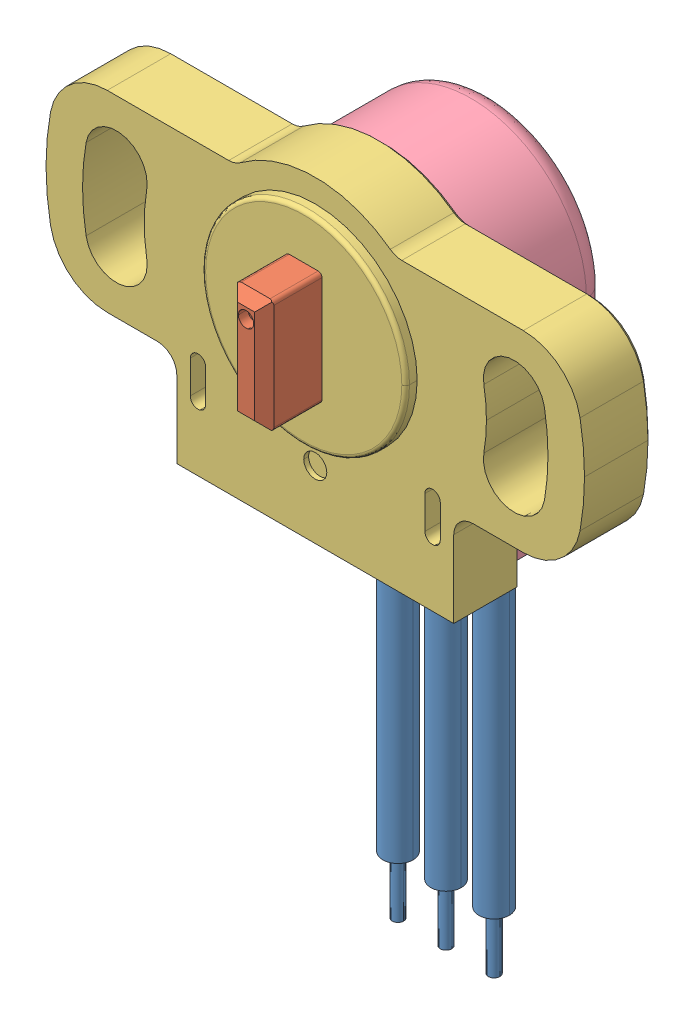
SolidWorks assembly BR-00009-DA-BPPS (MSC360-1A-C0004-ERA360-05K), configuration Default. Lengths in mm.
Overall size (28 38 12.8).
9 component instances, 4 part files, 0 mates.
Components (placement in the parent):
- MSC-360^BR-00009-DA-BPPS (MSC360-1A-C0004-ERA360-05K)-1: MSC-360^BR-00009-DA-BPPS (MSC360-1A-C0004-ERA360-05K) [Default] at origin size (28 38 12.8) (virtual)
  - 3981_subjto PCB^MSC-360_BR-00009-DA-BPPS (MSC360-1A-C0004-ERA360-05K)-1: 3981_subjto PCB^MSC-360_BR-00009-DA-BPPS (MSC360-1A-C0004-ERA360-05K) [Default] at (0 0 7.7) x (-1 0 0) z (0 0 -1) size (6.58 26 1.58) (virtual)
    - 3980_cable^3981_subjto PCB_MSC-360_BR-00009-DA-BPPS (MSC360-1A-C0004-ERA360-05K)-1: 3980_cable^3981_subjto PCB_MSC-360_BR-00009-DA-BPPS (MSC360-1A-C0004-ERA360-05K) [Default] at (0 -8.5 5.3) x (-1 0 0) z (0 -1 0) size (1.58 1.58 26) (virtual)
    - 3980_cable^3981_subjto PCB_MSC-360_BR-00009-DA-BPPS (MSC360-1A-C0004-ERA360-05K)-2: 3980_cable^3981_subjto PCB_MSC-360_BR-00009-DA-BPPS (MSC360-1A-C0004-ERA360-05K) [Default] at (2.5 -8.5 5.3) x (-1 0 0) z (0 -1 0) size (1.58 1.58 26) (virtual)
    - 3980_cable^3981_subjto PCB_MSC-360_BR-00009-DA-BPPS (MSC360-1A-C0004-ERA360-05K)-3: 3980_cable^3981_subjto PCB_MSC-360_BR-00009-DA-BPPS (MSC360-1A-C0004-ERA360-05K) [Default] at (-2.5 -8.5 5.3) x (-1 0 0) z (0 -1 0) size (1.58 1.58 26) (virtual)
  - 3987 rotor sobremoldeo^MSC-360_BR-00009-DA-BPPS (MSC360-1A-C0004-ERA360-05K)-1: 3987 rotor sobremoldeo^MSC-360_BR-00009-DA-BPPS (MSC360-1A-C0004-ERA360-05K) [Default] at (0 0 7.7) x (-1 0 0) z (0 0 1) size (1.9 5.9 3) (virtual)
    - 3987_rotor sobremoldeado^3987 rotor sobremoldeo_MSC-360_BR-00009-DA-BPPS (MSC360-1A-C0004-ERA360-05K)-1: 3987_rotor sobremoldeado^3987 rotor sobremoldeo_MSC-360_BR-00009-DA-BPPS (MSC360-1A-C0004-ERA360-05K) [Default] at origin size (1.9 5.9 3) (virtual)
  - 4048_carcasa MSC-360-G01-001^MSC-360_BR-00009-DA-BPPS (MSC360-1A-C0004-ERA360-05K)-1: 4048_carcasa MSC-360-G01-001^MSC-360_BR-00009-DA-BPPS (MSC360-1A-C0004-ERA360-05K) [Default] at origin size (28 16.5 9.5) (virtual)
  - 3982_apantallamiento^MSC-360_BR-00009-DA-BPPS (MSC360-1A-C0004-ERA360-05K)-1: 3982_apantallamiento^MSC-360_BR-00009-DA-BPPS (MSC360-1A-C0004-ERA360-05K) [Default] at origin size (12 16 7.5) (virtual)
